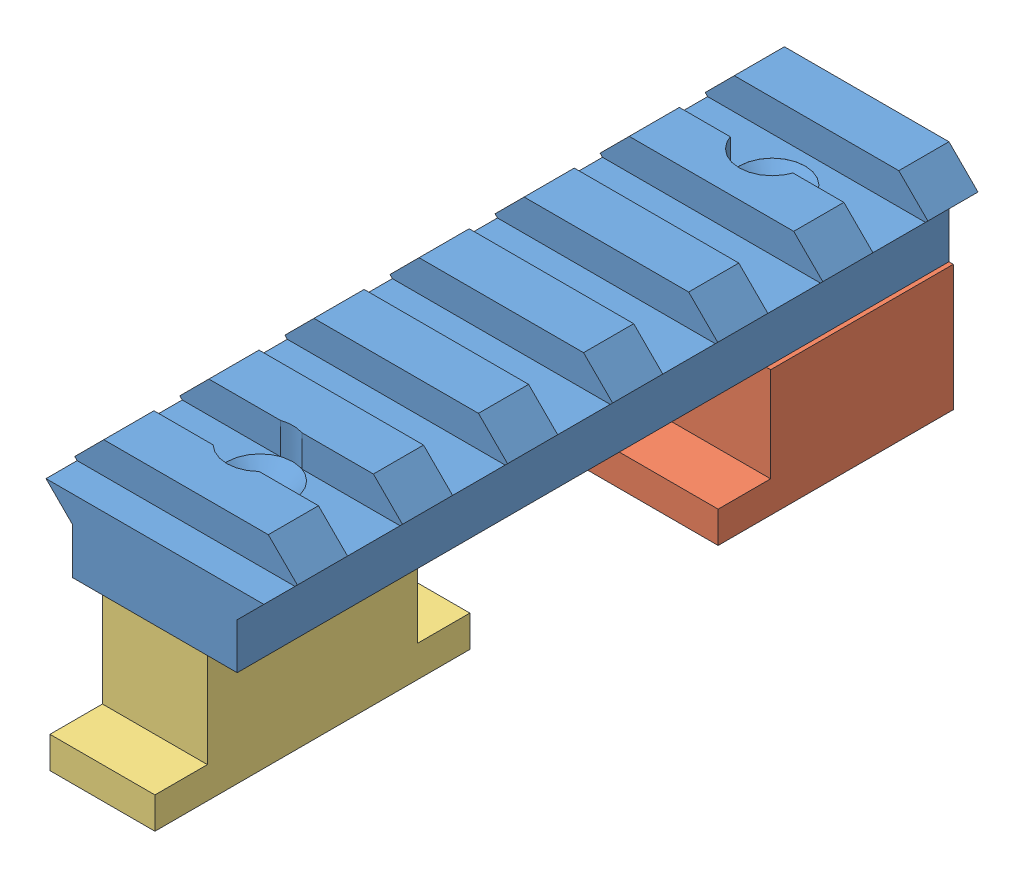
SolidWorks assembly Baugruppe1, configuration Standard. Lengths in mm.
Overall size (21.21 21.9 72.8).
3 component instances, 3 part files, 6 mates.
Components (placement in the parent):
- Rail-3: Rail [Standard] at (-4.1271 5.1584 0) size (21.21 9.9 67.8)
- flip_back-3: flip_back [Standard] at (-4.1271 -4.7457 0) x (0 0 1) z (-1 0 0) size (22.4 12 16.5)
- flip_front-1: flip_front [Standard] at (-4.1271 -4.7457 57.8) x (0 0 -1) z (1 0 0) size (30 12 10)
Mates (geometry in assembly coordinates):
- Deckungsgleich6: coincident: moEndPointRef_w of Rail-3; moEndPointRef_w of flip_back-3
- Deckungsgleich7: coincident anti-aligned: plane of Rail-3 through (-11.963 -4.7457 67.8) normal (0 -1 0); plane of flip_back-3 through (-12.3771 -4.7457 0) normal (0 1 0)
- Deckungsgleich8: coincident anti-aligned: line of Rail-3 through (-11.963 -4.7457 0) axis (1 0 0); line of flip_back-3 through (4.1229 -4.7457 0) axis (-1 0 0)
- Deckungsgleich9: coincident aligned: plane of Rail-3 through (-4.1271 12.9943 67.8) normal (0 0 1); plane of flip_front-1 through (0.8729 -13.7457 67.8) normal (0 0 1)
- Deckungsgleich10: coincident: moEndPointRef_w of flip_front-1; moEndPointRef_w of Rail-3
- Deckungsgleich11: coincident anti-aligned: plane of Rail-3 through (-11.963 -4.7457 67.8) normal (0 -1 0); plane of flip_front-1 through (0.8729 -4.7457 72.8) normal (0 1 0)
